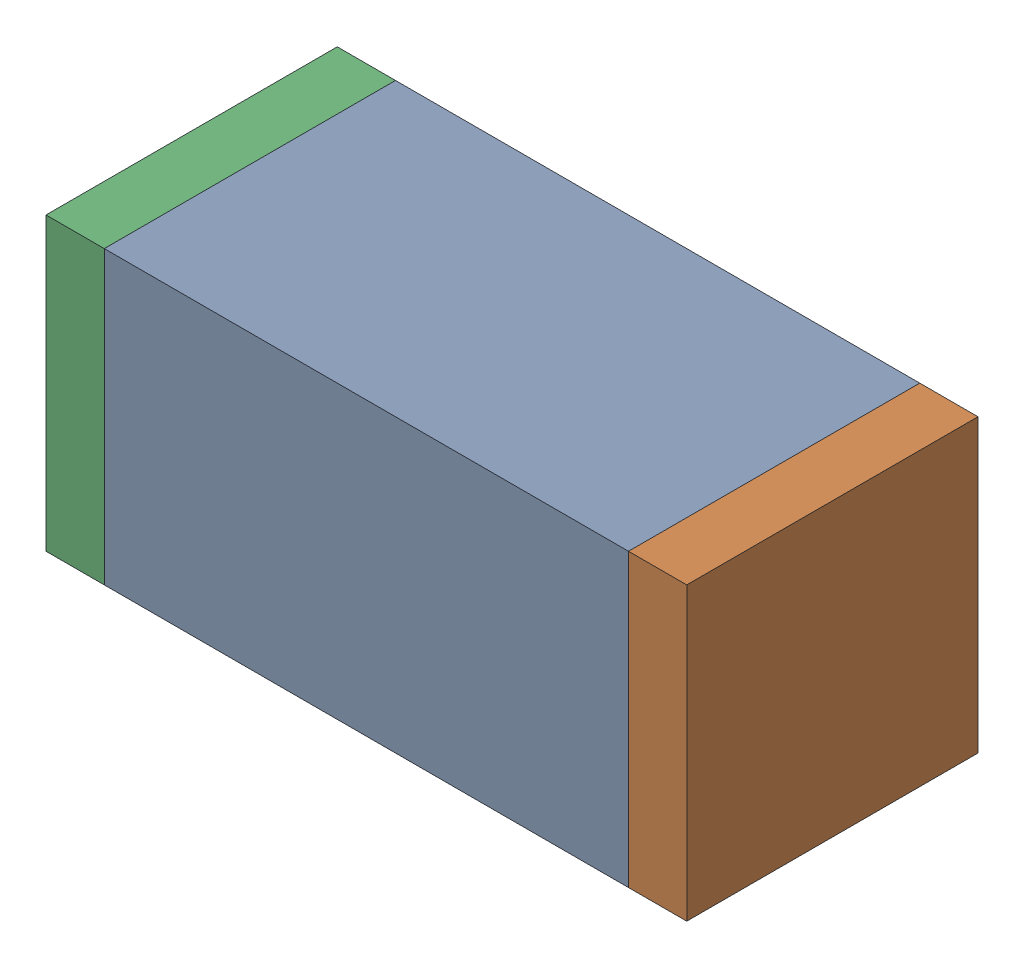
SolidWorks assembly C75, configuration Default. Lengths in mm.
Overall size (1.1 0.5 0.5).
6 component instances, 2 part files, 0 mates.
Components (placement in the parent):
- 836749680-1: 836749680 [Default] at (127.2 59.15 0) size (0.9 0.5 0.5)
  - Extruded_4-1: Extruded_4 [Default] at origin size (0.9 0.5 0.5)
- 810156080-1: 810156080 [Default] at (127.7 59.15 0) size (0.1 0.5 0.5)
  - Extruded_5-1: Extruded_5 [Default] at origin size (0.1 0.5 0.5)
- 810156080-2: 810156080 [Default] at (126.7 59.15 0) size (0.1 0.5 0.5)
  - Extruded_5-1: Extruded_5 [Default] at origin size (0.1 0.5 0.5)
